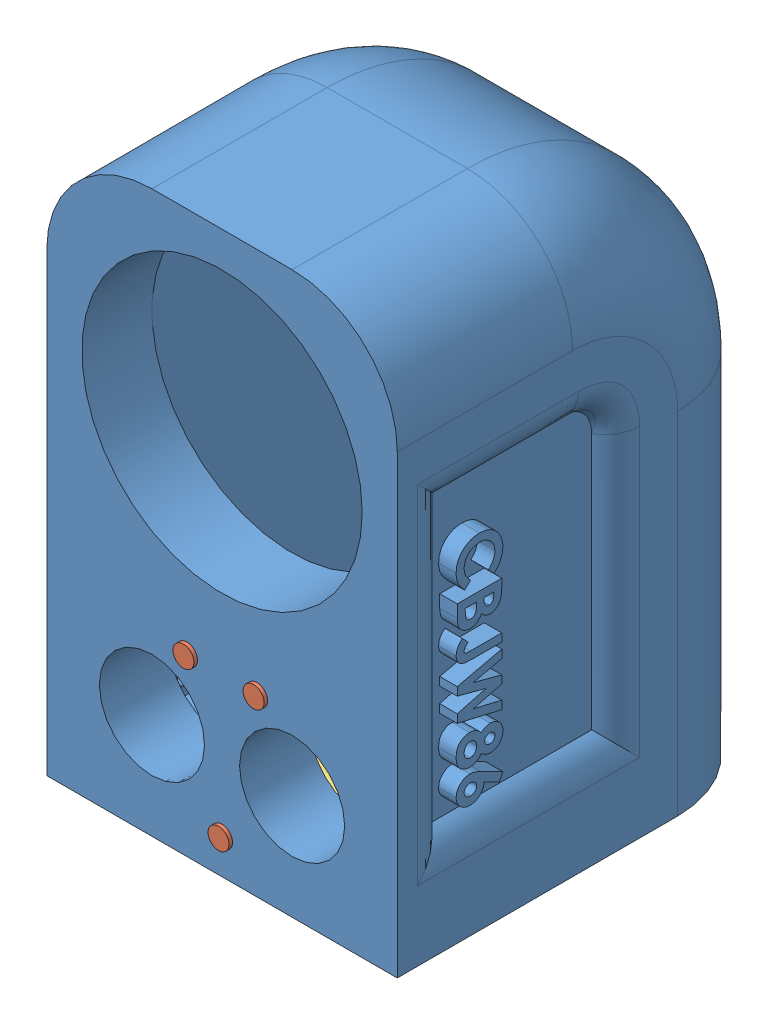
SolidWorks assembly SpeakerAssembl (1), configuration Default. Lengths in mm.
Overall size (100 160.32 111).
12 component instances, 7 part files, 27 mates.
Components (placement in the parent):
- speakerCAD-1: speakerCAD [Default] at (56.9986 106.0943 64.7796) size (100 160 110)
- Speaker_Driver_80mm-1: Speaker_Driver_80mm [Default] at (56.9986 136.0943 159.1683) (suppressed, hidden)
- Speaker_Driver_30mm-1: Speaker_Driver_30mm [Default] at (76.9986 56.0943 168.9254) x (0.756716 0.653743 0) z (0 0 1) (suppressed, hidden)
- Speaker_Driver_30mm-2: Speaker_Driver_30mm [Default] at (36.9986 56.0943 168.9254) x (0.93732 0.34847 0) z (0 0 1) (suppressed, hidden)
- Speaker_Button_Mount-1: Speaker_Button_Mount [Default] at (33.2599 61.6367 154.7796) x (-1 0 0) z (0 1 0) (suppressed, hidden)
- Speaker_Button_Mount-2: Speaker_Button_Mount [Default] at (13.2599 61.6367 154.7796) x (-1 0 0) z (0 1 0) (suppressed, hidden)
- Speaker_Button_Mount-3: Speaker_Button_Mount [Default] at (42.541 69.833 154.7796) x (0 1 0) z (1 0 0) (suppressed, hidden)
- Speaker_PCB-2: Speaker_PCB [Default] at (81.5251 46.8443 135.3592) x (1 0 0) z (0 1 0) (suppressed, hidden)
- ButtonCaps-1: ButtonCaps [Default] at (56.9986 36.0943 175.7796) x (1 0 0) z (0 0 -1) size (6 6 20)
- ButtonCaps-2: ButtonCaps [Default] at (46.9986 76.0943 175.7796) x (-0.964828 -0.262882 0) z (0 0 -1) size (6 6 20)
- ButtonCaps-3: ButtonCaps [Default] at (66.9986 76.0943 175.7796) x (-0.841297 -0.540574 0) z (0 0 -1) size (6 6 20)
- Base PLug-1: Base PLug [Default] at (56.9986 25.7693 125.734) x (-0.341232 0 -0.939979) z (0.939979 0 -0.341232) size (70 4.7 70)
Mates (geometry in assembly coordinates):
- Concentric1: concentric aligned: cylinder of speakerCAD-1 through (56.9986 136.0943 154.7796) axis (0 0 1) radius 40; cylinder of Speaker_Driver_80mm-1 through (56.9986 136.0943 149.5683) axis (0 0 1) radius 14.1177
- Coincident2: coincident anti-aligned: plane of speakerCAD-1 through (56.9986 106.0943 174.7796) normal (0 0 1); plane of Speaker_Driver_80mm-1 through (18.799 136.0943 174.7796) normal (0 0 -1)
- Concentric2: concentric aligned: cylinder of speakerCAD-1 through (36.9986 56.0943 154.7796) axis (0 0 1) radius 15; cylinder of Speaker_Driver_30mm-2 through (36.9986 56.0943 165.3254) axis (0 0 1) radius 5.2941
- Coincident3: coincident anti-aligned: plane of speakerCAD-1 through (56.9986 106.0943 174.7796) normal (0 0 1); plane of Speaker_Driver_30mm-2 through (23.5717 51.1025 174.7796) normal (0 0 -1)
- Concentric3: concentric aligned: cylinder of speakerCAD-1 through (76.9986 56.0943 154.7796) axis (0 0 1) radius 15; cylinder of Speaker_Driver_30mm-1 through (76.9986 56.0943 165.3254) axis (0 0 1) radius 5.2941
- Coincident4: coincident anti-aligned: plane of speakerCAD-1 through (56.9986 106.0943 174.7796) normal (0 0 1); plane of Speaker_Driver_30mm-1 through (66.1588 46.7295 174.7796) normal (0 0 -1)
- Coincident6: coincident aligned: plane of speakerCAD-1 through (6.9986 26.0943 174.7796) normal (-1 0 0); plane of Speaker_PCB-2 through (6.9986 41.0943 106.0196) normal (-1 0 0)
- Parallel1: parallel aligned: plane of speakerCAD-1 through (6.9986 26.0943 174.7796) normal (0 -1 0); plane of Speaker_PCB-2 through (32.418 45.8443 144.3946) normal (0 -1 0)
- Coincident9: coincident aligned: plane of speakerCAD-1 through (6.9986 26.0943 174.7796) normal (-1 0 0); plane of Speaker_PCB-2 through (6.9986 41.0943 144.7696) normal (-1 0 0)
- Concentric6: concentric anti-aligned: cylinder of Speaker_Button_Mount-3 through (56.9986 36.0943 165.7796) axis (0 0 -1) radius 2; cylinder of ButtonCaps-1 through (56.9986 36.0943 155.7796) axis (0 0 1) radius 2
- Coincident14: coincident anti-aligned: plane of Speaker_Button_Mount-3 through (56.9986 36.0943 165.7796) normal (0 0 1); plane of ButtonCaps-1 through (56.9986 36.0943 165.7796) normal (0 0 -1)
- Coincident15: coincident anti-aligned: plane of speakerCAD-1 through (76.9986 56.0943 154.7796) normal (0 0 -1); plane of Speaker_Button_Mount-3 through (61.7486 41.7193 154.7796) normal (0 0 1)
- Concentric8: concentric aligned: cylinder of speakerCAD-1 through (56.9986 36.0943 154.7796) axis (0 0 1) radius 3; cylinder of ButtonCaps-1 through (56.9986 36.0943 155.7796) axis (0 0 1) radius 3
- Parallel2: parallel aligned: plane of speakerCAD-1 through (6.9986 26.0943 174.7796) normal (0 -1 0); plane of Speaker_Button_Mount-3 through (52.2486 30.4693 144.7796) normal (0 -1 0)
- Concentric9: concentric anti-aligned: cylinder of Speaker_Button_Mount-1 through (66.9986 76.0943 165.7796) axis (0 0 -1) radius 2; cylinder of ButtonCaps-3 through (66.9986 76.0943 155.7796) axis (0 0 1) radius 2
- Coincident17: coincident anti-aligned: plane of Speaker_Button_Mount-1 through (66.9986 76.0943 165.7796) normal (0 0 1); plane of ButtonCaps-3 through (66.9986 76.0943 165.7796) normal (0 0 -1)
- Concentric10: concentric anti-aligned: cylinder of Speaker_Button_Mount-2 through (46.9986 76.0943 165.7796) axis (0 0 -1) radius 2; cylinder of ButtonCaps-2 through (46.9986 76.0943 155.7796) axis (0 0 1) radius 2
- Coincident18: coincident anti-aligned: plane of Speaker_Button_Mount-2 through (46.9986 76.0943 165.7796) normal (0 0 1); plane of ButtonCaps-2 through (46.9986 76.0943 165.7796) normal (0 0 -1)
- Concentric11: concentric aligned: cylinder of speakerCAD-1 through (66.9986 76.0943 154.7796) axis (0 0 1) radius 3; cylinder of ButtonCaps-3 through (66.9986 76.0943 155.7796) axis (0 0 1) radius 3
- Coincident19: coincident anti-aligned: plane of speakerCAD-1 through (76.9986 56.0943 154.7796) normal (0 0 -1); plane of Speaker_Button_Mount-1 through (61.3736 80.8443 154.7796) normal (0 0 1)
- Parallel3: parallel aligned: plane of speakerCAD-1 through (6.9986 26.0943 174.7796) normal (0 -1 0); plane of Speaker_Button_Mount-1 through (70.1236 71.3443 144.7796) normal (0 -1 0)
- Concentric12: concentric aligned: cylinder of speakerCAD-1 through (46.9986 76.0943 154.7796) axis (0 0 1) radius 3; cylinder of ButtonCaps-2 through (46.9986 76.0943 155.7796) axis (0 0 1) radius 3
- Coincident21: coincident anti-aligned: plane of speakerCAD-1 through (76.9986 56.0943 154.7796) normal (0 0 -1); plane of Speaker_Button_Mount-2 through (41.3736 80.8443 154.7796) normal (0 0 1)
- Parallel4: parallel aligned: plane of speakerCAD-1 through (6.9986 26.0943 174.7796) normal (0 -1 0); plane of Speaker_Button_Mount-2 through (50.1236 71.3443 144.7796) normal (0 -1 0)
- Concentric13: concentric anti-aligned: cylinder of speakerCAD-1 through (16.9986 41.0943 106.0196) axis (-1 0 0) radius 2.75; cylinder of Speaker_PCB-2 through (6.9986 41.0943 106.0196) axis (1 0 0) radius 2.75
- Concentric14: concentric aligned: cylinder of speakerCAD-1 through (56.9986 36.0943 125.734) axis (0 -1 0) radius 35; cylinder of Base PLug-1 through (56.9986 30.4693 125.734) axis (0 -1 0) radius 35
- Coincident23: coincident anti-aligned: plane of Speaker_Button_Mount-3 through (52.2486 30.4693 144.7796) normal (0 -1 0); plane of Base PLug-1 through (56.9986 30.4693 125.734) normal (0 1 0)
